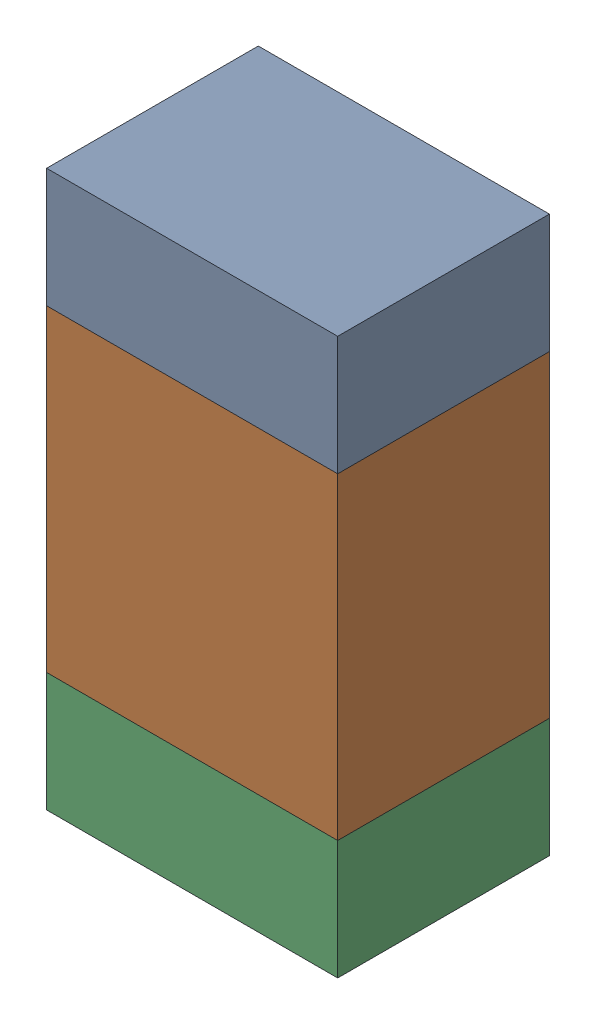
SolidWorks assembly R203PCB, configuration Default. Lengths in mm.
Overall size (0.55 1.05 0.4).
6 component instances, 2 part files, 0 mates.
Components (placement in the parent):
- 846483288-1: 846483288 [Default] at (90.0001 125.2124 0) size (0.55 0.22 0.4)
  - Extruded_12-1: Extruded_12 [Default] at origin size (0.55 0.22 0.4)
- 846483424-1: 846483424 [Default] at (90.0001 124.7999 0) size (0.55 0.6 0.4)
  - Extruded_13-1: Extruded_13 [Default] at origin size (0.55 0.6 0.4)
- 846483288-2: 846483288 [Default] at (90.0001 124.3874 0) size (0.55 0.22 0.4)
  - Extruded_12-1: Extruded_12 [Default] at origin size (0.55 0.22 0.4)
